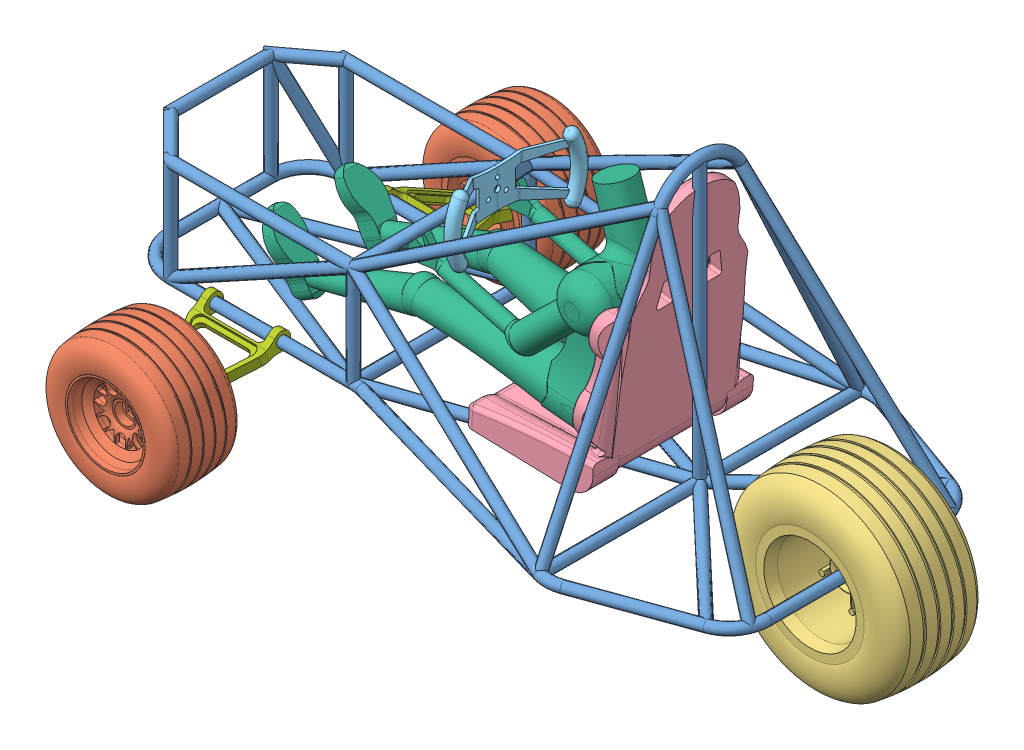
SolidWorks assembly ConceptDesignAssembly, configuration Default. Lengths in mm.
Overall size (1663.67 996.21 925.64).
9 component instances, 7 part files, 4 mates.
Components (placement in the parent):
- Chassis_Concept-1: Chassis_Concept [Default<As Machined>] at (-99.0739 393.6278 971.7878) size (1302.44 589.73 677.29)
- roue arrière bridgestone potenza f1 Rc-1: roue arrière bridgestone potenza f1 Rc [Défaut] at (121.3266 364.7471 1352.627) x (0.008727 0 0.999962) z (-0.999962 0 0.008727) size (156.43 504.25 800)
- roue avant bridgestone potenza f1 Rc-1: roue avant bridgestone potenza f1 Rc [Défaut] at (1180.3766 413.5562 969.0976) x (0 0 -1) z (0.996421 0.084534 0) size (186.28 556.83 1126.53)
- seat-1: seat [Default] at (483.1621 432.2617 969.9339) x (0.999613 -0.027819 0) z (0 0 1) size (306.12 507.2 325.57)
- roue arrière bridgestone potenza f1 Rc-3: roue arrière bridgestone potenza f1 Rc [Défaut] at (121.3266 324.7472 590.9487) x (0.008727 0 -0.999962) z (-0.999962 0 -0.008727) size (156.43 504.25 800)
- butterfly-steering-wheel-1: butterfly-steering-wheel [Default] at (458.2557 704.7706 974.8906) x (0.008727 0 -0.999962) z (0.999962 0 0.008727) size (279.4 150.78 59.13)
- dummydriver-1: dummydriver [Default] at (757.0351 864.14 979.1441) x (-0.002769 0.008276 0.999962) z (-0.317293 0.948288 -0.008727) size (261 742.26 387.15)
- Lower Panel-1: Lower Panel [Default] at (126.9283 21.7418 2048.3238) x (1 0 0) z (0 -0.924494 -0.381196) size (150.5 262.84 46.5)
- Lower Panel-2: Lower Panel [Default] at (125.5669 81.3752 -127.1658) x (1 0 0) z (0 0.946666 -0.322216) size (150.5 262.84 46.5)
Mates (geometry in assembly coordinates):
- Parallel1: parallel: line of Chassis_Concept-1 through (-99.0739 393.6278 1073.3878) axis (0 0 -1); plane of seat-1 through (554.6896 447.3004 1093.7531) normal (-0.999613 0.027819 0)
- Concentric1: concentric: cylinder of Chassis_Concept-1 through (1182.0672 393.6278 796.7463) axis (0 0 1) radius 10.65; cylinder of roue avant bridgestone potenza f1 Rc-1 through (1182.0672 393.6278 1058.8991) axis (0 0 -1) radius 13.75
- Concentric2: concentric: cylinder of Chassis_Concept-1 through (-22.8739 393.6278 793.9878) axis (1 0 0) radius 10.65; cylinder of Lower Panel-2 through (125.5952 393.6278 793.9878) axis (1 0 0) radius 10.5
- Concentric3: concentric: cylinder of Chassis_Concept-1 through (347.4169 393.6278 1149.5878) axis (-1 0 0) radius 10.65; cylinder of Lower Panel-1 through (126.9567 393.6278 1149.5878) axis (1 0 0) radius 10.5
